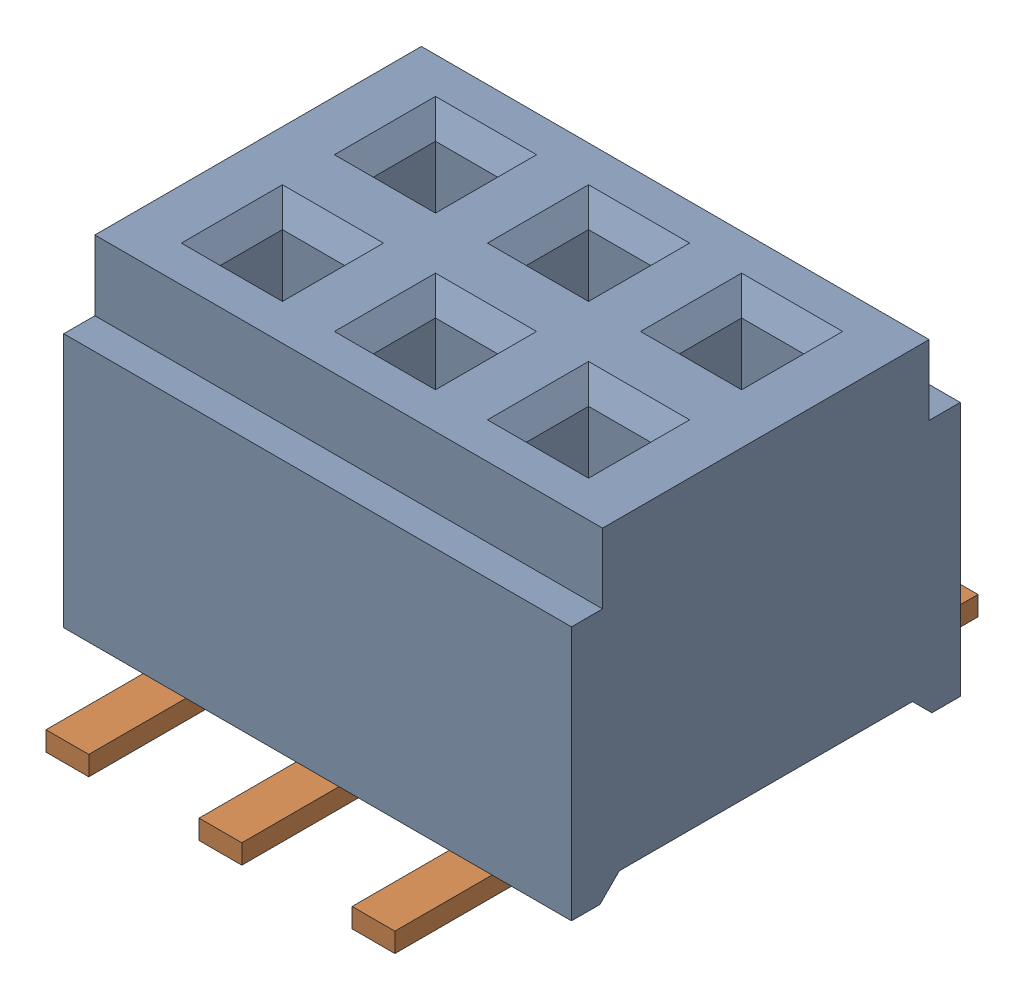
SolidWorks assembly CLM-103-02-F-D, configuration ﾃﾞﾌｫﾙﾄ. Lengths in mm.
Overall size (3.32 2.25 3.81).
2 component instances, 2 part files, 0 mates.
Components (placement in the parent):
- _CLM-103-02-F-D_socket-1: _CLM-103-02-F-D_socket [ﾃﾞﾌｫﾙﾄ] at (-1.6587 0 0) size (3.32 2.12 2.54)
- _C-03-02_pins-1: _C-03-02_pins [ﾃﾞﾌｫﾙﾄ] at origin size (2.99 1.14 3.81)
